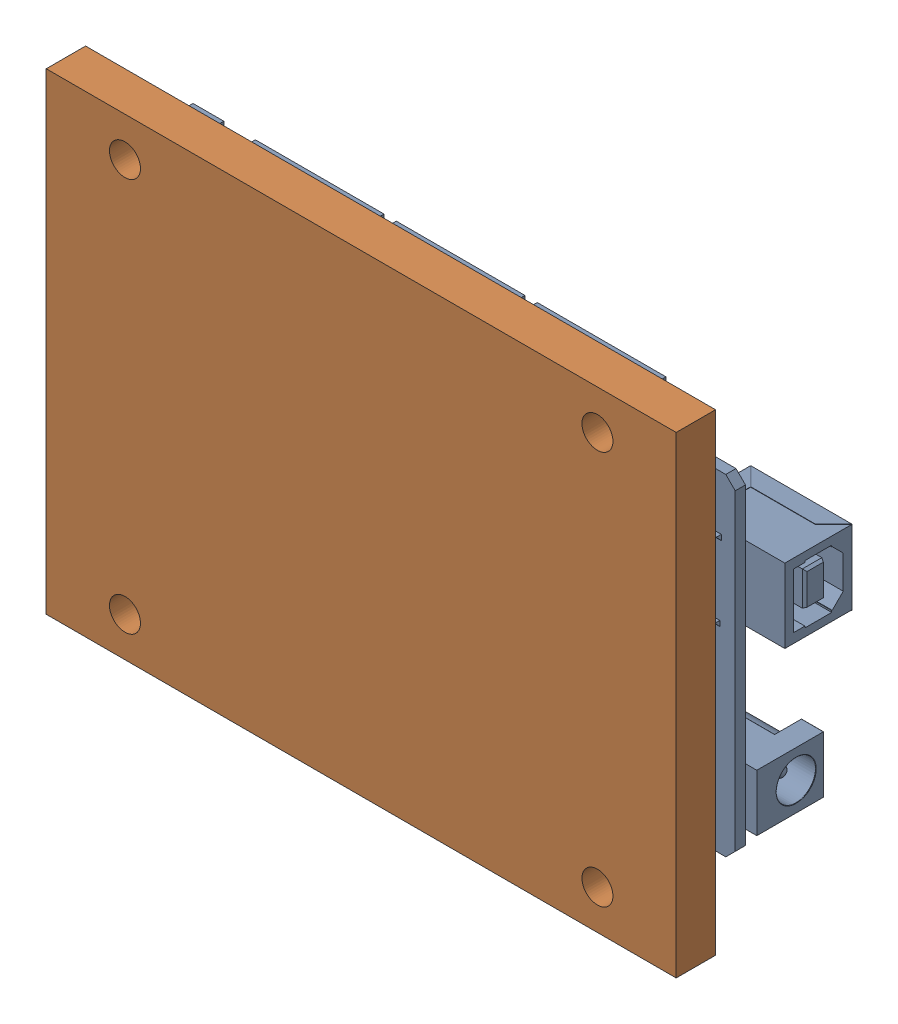
SolidWorks assembly MegaAssembly, configuration Default. Lengths in mm.
Overall size (107.95 76.2 21.97).
2 component instances, 2 part files, 4 mates.
Components (placement in the parent):
- ArduinoMega-2: ArduinoMega [Default] at (-16.7528 4.2196 8.6161) size (107.95 53.42 12.95)
- MegaStand-1: MegaStand [Default] at (-16.7528 4.2196 19.7921) x (0 1 0) z (-1 0 0) size (76.2 12.7 101.6)
Mates (geometry in assembly coordinates):
- Width1: width anti-aligned: plane of MegaStand-1 through (-67.5528 -33.8804 13.4421) normal (0 -1 0); plane of ArduinoMega-2 through (-67.5528 42.3196 13.4421) normal (0 1 0); plane of MegaStand-1 through (-67.5528 30.9277 10.2671) normal (0 1 0); plane of ArduinoMega-2 through (-67.5528 -22.4885 10.2671) normal (0 -1 0)
- Parallel2: parallel anti-aligned: plane of ArduinoMega-2 through (34.0472 -22.4885 10.2671) normal (0 0 1); plane of MegaStand-1 through (-16.7528 4.2196 13.4421) normal (0 0 -1)
- Width2: width anti-aligned: plane of MegaStand-1 through (-67.5528 -33.8804 13.4421) normal (-1 0 0); plane of ArduinoMega-2 through (34.0472 -33.8804 13.4421) normal (1 0 0); plane of MegaStand-1 through (34.0472 30.9277 10.2671) normal (1 0 0); plane of ArduinoMega-2 through (-67.5528 30.9277 10.2671) normal (-1 0 0)
- Coincident1: coincident anti-aligned: plane of ArduinoMega-2 through (34.0472 -22.4885 10.2671) normal (0 0 1); plane of MegaStand-1 through (-16.7528 4.2196 10.2671) normal (0 0 -1)
